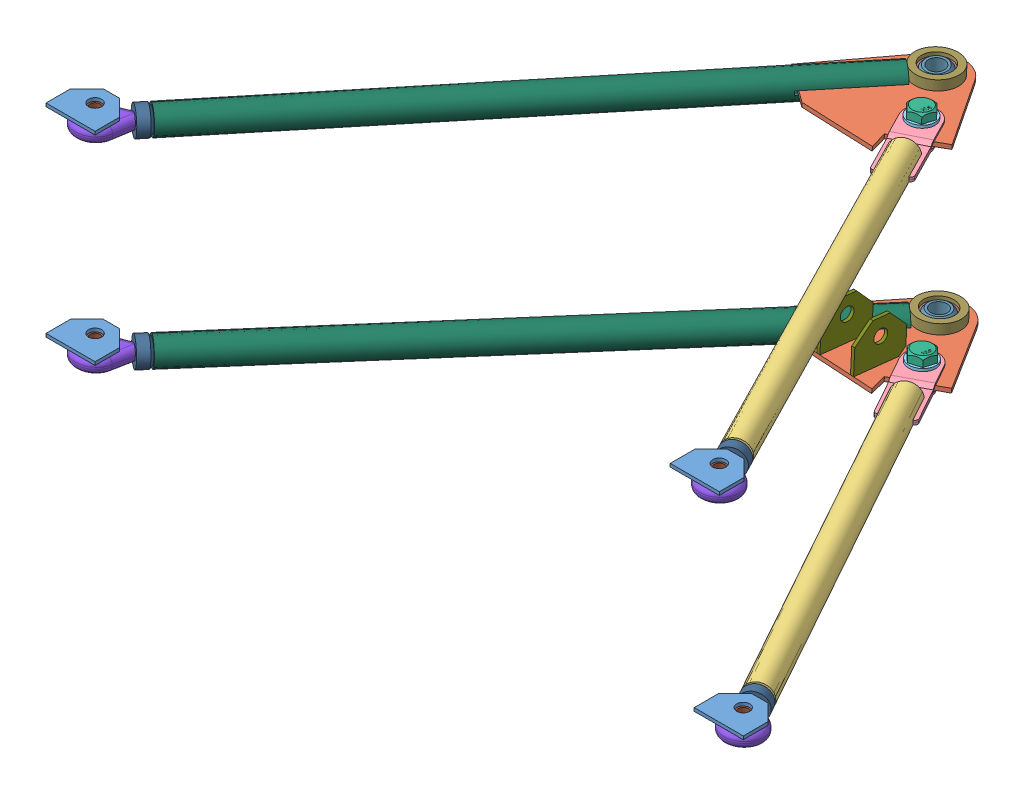
SolidWorks assembly Bell Crank and Control Arms V4, configuration Default. Lengths in mm.
Overall size (449.35 166.14 366.09).
52 component instances, 16 part files, 12 mates.
Components (placement in the parent):
- frame connectors-10: frame connectors [Default] at (-357.6393 7.7366 39.1204) size (30 2 25)
- frame connectors-11: frame connectors [Default] at (24.0053 7.7366 39.1204) size (30 2 25)
- Upper Control Arm Assembly-1: Upper Control Arm Assembly [Default] at (-132.0035 -138.9023 -250.945) x (0.997989 0.003304 0.063309) z (-0.063395 0.052016 0.996632) size (428.79 42.68 337.86) (flexible)
  - Front Control Arm Plate-1: Front Control Arm Plate [Default] at origin size (91 2.5 76.52)
  - Rear Upper Control Arm-2: Rear Upper Control Arm [Default] at (105.6055 0 154.4308) x (-0.554844 0 -0.831954) z (0.831954 0 -0.554844) size (250 16 16)
  - Control Arm Link Plate-1: Control Arm Link Plate [Default] at (31.8652 1.25 43.6848) x (-0.554844 0 -0.831954) z (0.831954 0 -0.554844) size (54.1 2.5 20)
  - Control Arm Link Plate-2: Control Arm Link Plate [Default] at (31.8652 -1.25 43.6848) x (-0.554844 0 -0.831954) z (-0.831954 0 0.554844) size (54.1 2.5 20)
  - plain washer normal grade a_iso-1: plain washer normal grade a_iso [Washer ISO 7089 - 8] at (22.4051 2.5 29.5) x (0 -1 0) z (0.774417 0 0.632675) size (1.6 16 16)
  - 94863A205_High-Strength Class 10.9 Steel Hex Head Screw-1: 94863A205_High-Strength Class 10.9 Steel Hex Head Screw [94863A205] at (22.4051 4.1 29.5) x (0.632675 0 -0.774417) z (0 1 0) size (13 16.35 25.89)
  - 94645A111_High-Strength Steel Nylon-Insert Locknut-1: 94645A111_High-Strength Steel Nylon-Insert Locknut [94645A111] at (22.4051 -6.5 29.5) x (-0.775473 0 -0.631381) z (-0.631381 0 0.775473) size (13 8 14.93)
  - Link Insert Assembly-1: Link Insert Assembly [Default] at (151.1806 41.9532 246.62) x (0.831954 0 -0.554844) z (0 -1 0) size (24 54 13.75) (flexible)
    - Link-1: Link [Default] at (13.2343 18.3157 41.9532) size (24 54 13.75)
    - Spherical Bearing Ball-1: Spherical Bearing Ball [Default] at (13.2343 47.8157 41.9532) x (0.026112 -0.045108 0.998641) z (0.47455 -0.878686 -0.052098) size (9 13.75 13.75)
  - Control Arm Insert-1: Control Arm Insert [Default] at (162.0573 0 239.0767) x (-0.831525 0.032128 0.554558) z (0.026729 0.999484 -0.017826) size (16 25 16)
  - 8mm Spehrical Bearing Insert-1: 8mm Spehrical Bearing Insert [Default] at (188.7427 6.4912 279.3957) x (-0.332123 0.050159 -0.941902) z (-0.94323 -0.014163 0.331837) size (11 9 11)
  - Spherical Bearing Seat-1: Spherical Bearing Seat [Default] at (0 -0.3 0) size (30 15.1 30)
  - Wide Spherical Bearing-1: Wide Spherical Bearing [Default] at (-7.3247 -16.3877 13.3464) x (1 0 0) z (0 1 0) size (26.76 26.96 14.68) (flexible)
    - Wide Bearing Cage-1: Wide Bearing Cage [Default] at (7.3247 13.3464 16.0877) size (22 22 10.5)
    - Wide Ball-1: Wide Ball [Default] at (7.3247 13.3464 16.0877) x (-0.803355 0.595088 0.022163) z (0.009626 -0.024235 0.99966) size (19.04 19.04 14)
  - Front Upper Control Arm-1: Front Upper Control Arm [Default] at (-100.6334 0 146.8287) x (0.559193 0 -0.829038) z (0.829038 0 0.559193) size (330 16 16)
  - Link Insert Assembly-2: Link Insert Assembly [Default] at (-191.0018 41.9532 257.1385) x (0.829038 0 0.559193) z (0 -1 0) size (24 54 13.75) (flexible)
    - Link-1: Link [Default] at (13.2343 18.3157 41.9532) size (24 54 13.75)
    - Spherical Bearing Ball-1: Spherical Bearing Ball [Default] at (13.2343 47.8157 41.9532) x (-0.031826 -0.041275 0.998641) z (-0.686072 -0.725683 -0.051858) size (9 13.75 13.75)
  - Control Arm Insert-2: Control Arm Insert [Default] at (-179.8953 0 264.3393) x (-0.82861 0.032128 -0.558904) z (0.026635 0.999484 0.017966) size (16 25 16)
  - 8mm Spehrical Bearing Insert-2: 8mm Spehrical Bearing Insert [Default] at (-206.7468 6.4912 304.5181) x (-0.995539 0.00819 -0.093998) z (-0.094297 -0.051473 0.994213) size (11 9 11)
  - Push Rod Upper Control Arm Bracket-1: Push Rod Upper Control Arm Bracket [Default] at (10.7762 13.75 44.5) x (0 0 1) z (0 -1 0) size (30 2 25)
  - Push Rod Upper Control Arm Bracket-2: Push Rod Upper Control Arm Bracket [Default] at (-11.2238 13.75 44.5) x (0 0 1) z (0 -1 0) size (30 2 25)
- frame connectors-14: frame connectors [Default] at (-357.6393 -114.2634 39.1204) size (30 2 25)
- frame connectors-15: frame connectors [Default] at (38.6473 -114.2634 39.1204) size (30 2 25)
- Lower Control Arm Assembly-4: Lower Control Arm Assembly [Default] at (-138.1243 -15.115 -255.6905) x (0.999096 0.001924 0.042477) z (-0.04252 0.045201 0.998073) size (414.39 25.89 337.86) (flexible)
  - Front Control Arm Plate-1: Front Control Arm Plate [Default] at origin size (91 2.5 76.52)
  - Rear Upper Control Arm-2: Rear Upper Control Arm [Default] at (98.5019 0 158.8804) x (-0.507538 0 -0.861629) z (0.861629 0 -0.507538) size (250 16 16)
  - Control Arm Link Plate-1: Control Arm Link Plate [Default] at (31.0586 1.25 44.1908) x (-0.507538 0 -0.861629) z (0.861629 0 -0.507538) size (54.1 2.5 20)
  - Control Arm Link Plate-2: Control Arm Link Plate [Default] at (31.0586 -1.25 44.1908) x (-0.507538 0 -0.861629) z (-0.861629 0 0.507538) size (54.1 2.5 20)
  - plain washer normal grade a_iso-1: plain washer normal grade a_iso [Washer ISO 7089 - 8] at (22.4051 2.5 29.5) x (0 -1 0) z (0.737893 0 0.674918) size (1.6 16 16)
  - 94863A205_High-Strength Class 10.9 Steel Hex Head Screw-1: 94863A205_High-Strength Class 10.9 Steel Hex Head Screw [94863A205] at (22.4051 4.1 29.5) x (0.674918 0 -0.737893) z (0 1 0) size (13 16.35 25.89)
  - 94645A111_High-Strength Steel Nylon-Insert Locknut-1: 94645A111_High-Strength Steel Nylon-Insert Locknut [94645A111] at (22.4051 -6.5 29.5) x (-0.772835 0 -0.634608) z (-0.634608 0 0.772835) size (13 8 14.93)
  - Link Insert Assembly-1: Link Insert Assembly [Default] at (138.8598 41.9532 253.4699) x (0.861629 0 -0.507538) z (0 -1 0) size (24 54 13.75) (flexible)
    - Link-1: Link [Default] at (13.2343 18.3157 41.9532) size (24 54 13.75)
    - Spherical Bearing Ball-1: Spherical Bearing Ball [Default] at (13.2343 47.8157 41.9532) x (0.021284 -0.039923 0.998976) z (-0.188545 0.981113 0.043226) size (9 13.75 13.75)
  - Control Arm Insert-1: Control Arm Insert [Default] at (150.1406 0 246.5455) x (-0.861184 0.032128 0.507276) z (0.027682 0.999484 -0.016306) size (16 25 16)
  - 8mm Spehrical Bearing Insert-1: 8mm Spehrical Bearing Insert [Default] at (174.5437 6.4933 288.2463) x (0.55455 -0.03868 0.831251) z (0.832148 0.023467 -0.554057) size (11 9 11)
  - Spherical Bearing Seat-1: Spherical Bearing Seat [Default] at (0 -0.3 0) size (30 15.1 30)
  - Wide Spherical Bearing-1: Wide Spherical Bearing [Default] at (-7.3247 -16.3877 13.3464) x (1 0 0) z (0 1 0) size (26.99 27.46 16.25) (flexible)
    - Wide Bearing Cage-1: Wide Bearing Cage [Default] at (7.3247 13.3464 16.0877) size (22 22 10.5)
    - Wide Ball-1: Wide Ball [Default] at (7.3247 13.3464 16.0877) x (-0.82616 0.558017 0.077951) z (0.040218 -0.079591 0.996016) size (19.04 19.04 14)
  - Front Upper Control Arm-1: Front Upper Control Arm [Default] at (-100.6334 0 146.8287) x (0.559193 0 -0.829038) z (0.829038 0 0.559193) size (330 16 16)
  - Link Insert Assembly-2: Link Insert Assembly [Default] at (-191.0018 41.9532 257.1385) x (0.829038 0 0.559193) z (0 -1 0) size (24 54 13.75) (flexible)
    - Link-1: Link [Default] at (13.2343 18.3157 41.9532) size (24 54 13.75)
    - Spherical Bearing Ball-1: Spherical Bearing Ball [Default] at (13.2343 47.8157 41.9532) x (-0.026871 -0.036398 0.998976) z (-0.732376 -0.679448 -0.044456) size (9 13.75 13.75)
  - Control Arm Insert-2: Control Arm Insert [Default] at (-179.8953 0 264.3393) x (-0.82861 0.032128 -0.558904) z (0.026635 0.999484 0.017966) size (16 25 16)
  - 8mm Spehrical Bearing Insert-2: 8mm Spehrical Bearing Insert [Default] at (-206.7557 6.4933 304.4738) x (-0.995506 0.006193 -0.094494) z (-0.094678 -0.044816 0.994499) size (11 9 11)
Mates (geometry in assembly coordinates):
- Concentric18: concentric aligned: cylinder of frame connectors-10 through (-357.6393 8.7366 39.1204) axis (0 -1 0) radius 4; cylinder of frame connectors-14 through (-357.6393 -113.2634 39.1204) axis (0 -1 0) radius 4
- Coincident27: coincident aligned: plane of frame connectors-10 through (-372.6393 8.7366 54.1204) normal (0 0 1); plane of frame connectors-14 through (-372.6393 -113.2634 54.1204) normal (0 0 1)
- Distance2: distance = 120 mm anti-aligned: plane of frame connectors-14 through (-357.6393 -113.2634 39.1204) normal (0 1 0); plane of frame connectors-10 through (-357.6393 6.7366 39.1204) normal (0 -1 0)
- Concentric19: concentric aligned: cylinder of Upper Control Arm Assembly-1/8mm Spehrical Bearing Insert-2 through (-357.6393 -117.2634 39.1204) axis (0 -1 0) radius 3; cylinder of frame connectors-14 through (-357.6393 -113.2634 39.1204) axis (0 -1 0) radius 4
- Coincident29: coincident anti-aligned: plane of Upper Control Arm Assembly-1/8mm Spehrical Bearing Insert-2 through (-352.2076 -115.2634 39.9847) normal (0 1 0); plane of frame connectors-14 through (-357.6393 -115.2634 39.1204) normal (0 -1 0)
- Coincident30: coincident aligned: plane of frame connectors-14 through (-372.6393 -113.2634 54.1204) normal (0 0 1); plane of frame connectors-15 through (23.6473 -113.2634 54.1204) normal (0 0 1)
- Coincident31: coincident aligned: plane of frame connectors-14 through (-357.6393 -113.2634 39.1204) normal (0 1 0); plane of frame connectors-15 through (38.6473 -113.2634 39.1204) normal (0 1 0)
- Concentric20: concentric aligned: cylinder of Upper Control Arm Assembly-1/8mm Spehrical Bearing Insert-1 through (38.6473 -117.2634 39.1204) axis (0 -1 0) radius 3; cylinder of frame connectors-15 through (38.6473 -113.2634 39.1204) axis (0 -1 0) radius 4
- Coincident32: coincident anti-aligned: plane of Upper Control Arm Assembly-1/8mm Spehrical Bearing Insert-1 through (40.1419 -115.2634 44.4135) normal (0 1 0); plane of frame connectors-15 through (38.6473 -115.2634 39.1204) normal (0 -1 0)
- Concentric21: concentric aligned: cylinder of frame connectors-10 through (-357.6393 8.7366 39.1204) axis (0 -1 0) radius 4; circle of Lower Control Arm Assembly-4/8mm Spehrical Bearing Insert-2
- Coincident33: coincident anti-aligned: plane of frame connectors-10 through (-357.6393 6.7366 39.1204) normal (0 -1 0); plane of Lower Control Arm Assembly-4/8mm Spehrical Bearing Insert-2 through (-352.191 6.7366 39.8732) normal (0 1 0)
- Concentric22: concentric aligned: cylinder of frame connectors-11 through (24.0053 8.7366 39.1204) axis (0 -1 0) radius 4; cylinder of Lower Control Arm Assembly-4/8mm Spehrical Bearing Insert-1 through (24.0053 4.7366 39.1204) axis (0 -1 0) radius 3
